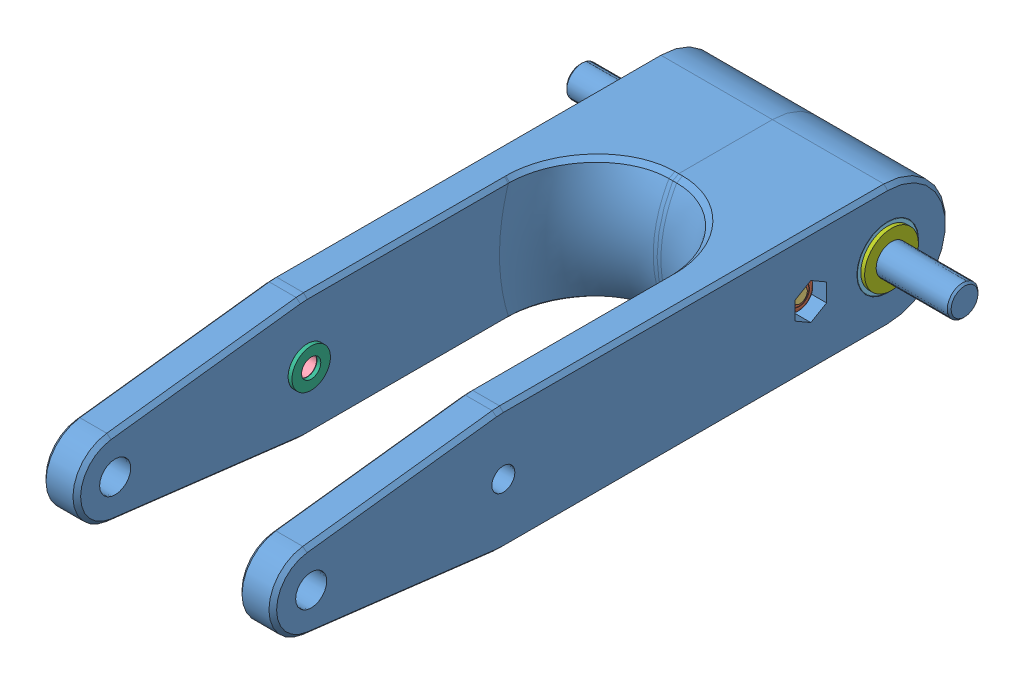
SolidWorks assembly Lon Rig Aft Arm, configuration Default. Lengths in mm.
Overall size (402.62 6573.27 2949.32).
10 component instances, 7 part files, 0 mates.
Components (placement in the parent):
- Lon Rig Aft Arm-1: Lon Rig Aft Arm [Default] at origin size (100 60.81 176)
- 93625A200 (1)-1: 93625A200 (1) [Default] at (-317.725 6533.262 2747.3504) x (0 0 1) z (0 1 0) size (8 5.15 9.24)
- 91294A224-1: 91294A224 [Default] at (-367.525 6533.262 2747.3504) x (0 0 -1) z (-1 0 0) size (16.38 17.42 62.07)
- Mini Ball Bearing 105zz 5x10x4 v2-1: Mini Ball Bearing 105zz 5x10x4 v2 [Default] at (-316.725 6533.262 2827.3504) x (0 0 -1) z (1 0 0) size (10 10 4)
- Mini Ball Bearing 105zz 5x10x4 v2-2: Mini Ball Bearing 105zz 5x10x4 v2 [Default] at (-362.725 6533.262 2827.3504) x (0 0 -1) z (1 0 0) size (10 10 4)
- 57485K67-1: 57485K67 [Default] at (-309.725 6533.262 2727.3504) x (0 1 0) z (-1 0 0) size (49.3 49.3 49.3)
- 57485K67-2: 57485K67 [Default] at (-361.725 6533.262 2727.3504) x (0 1 0) z (-1 0 0) size (49.3 49.3 49.3)
- 98089A375-1: 98089A375 [Default] at (-359.725 6533.262 2827.3504) x (0 0 -1) z (-1 0 0) size (10 10 1)
- 98089A381-1: 98089A381 [Default] at (-369.725 6533.262 2727.3504) x (0 0 1) z (-1 0 0) size (14 14 1)
- 98089A381-2: 98089A381 [Default] at (-308.725 6533.262 2727.3504) x (0 0 1) z (-1 0 0) size (14 14 1)
